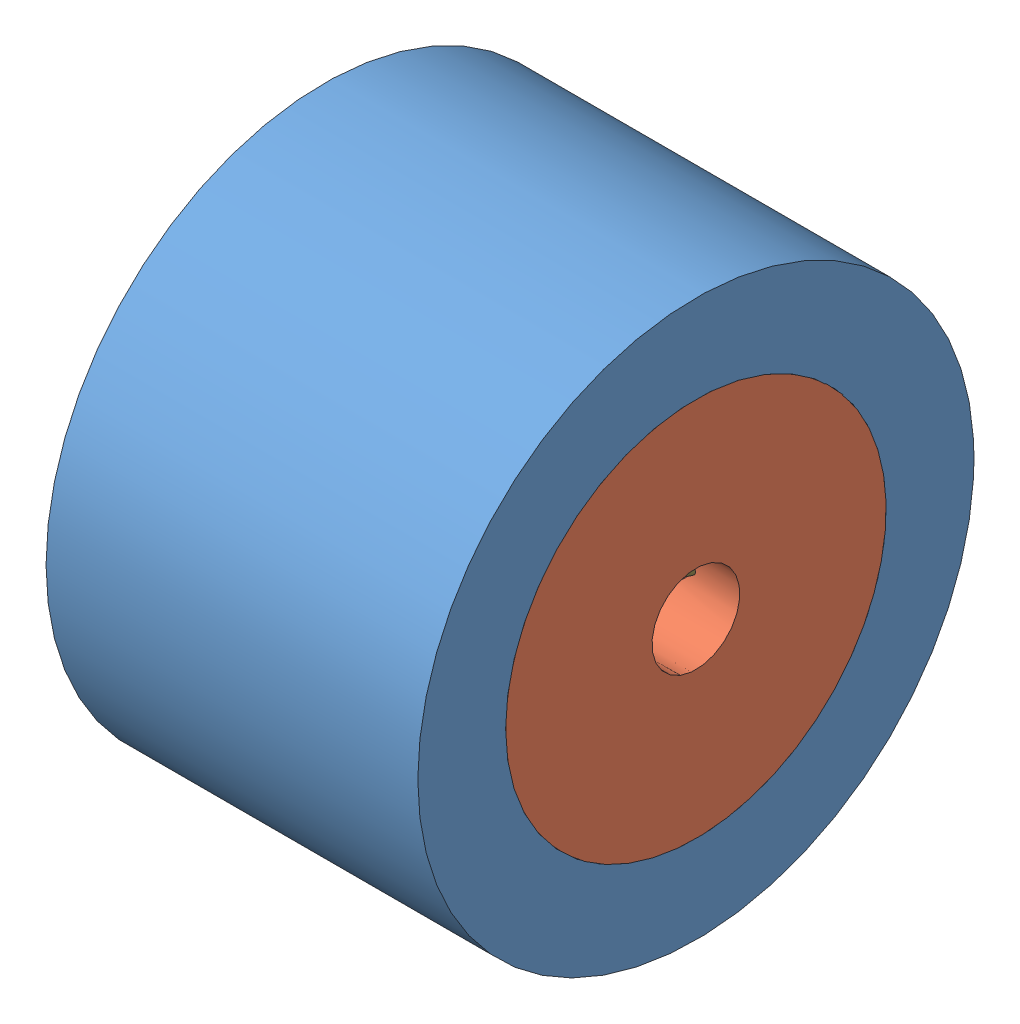
SolidWorks assembly wheel, configuration Default. Lengths in mm.
Overall size (12.7 18 18).
3 component instances, 3 part files, 4 mates.
Components (placement in the parent):
- tire-1: tire [Default] at origin size (12.7 18 18)
- hub-1: hub [Default] x (1 0 0) z (0 -0.9106 -0.413288) size (12.7 13 13)
- m3 x 6 setscrew 92605A100-1: m3 x 6 setscrew 92605A100 [92605A100] at (10.1049 1.6592 -3.6556) x (0 0.413288 -0.9106) z (0.981405 -0.174787 -0.079329) size (6.56 3.01 3.46)
Mates (geometry in assembly coordinates):
- Coincident1: coordinate: point of tire-1; point of assembly
- Concentric1: concentric aligned: cylinder of tire-1 through (12.7 0 0) axis (-1 0 0) radius 6.5; cylinder of hub-1 through (12.7 0 0) axis (-1 0 0) radius 6.5
- Coincident2: coincident aligned: plane of tire-1 through (12.7 0 0) normal (1 0 0); plane of hub-1 through (12.7 0 0) normal (1 0 0)
- Concentric3: concentric anti-aligned: cylinder of hub-1 through (10.1049 2.6864 -5.9189) axis (0 0.413288 -0.9106) radius 1.25; circle of m3 x 6 setscrew 92605A100-1
